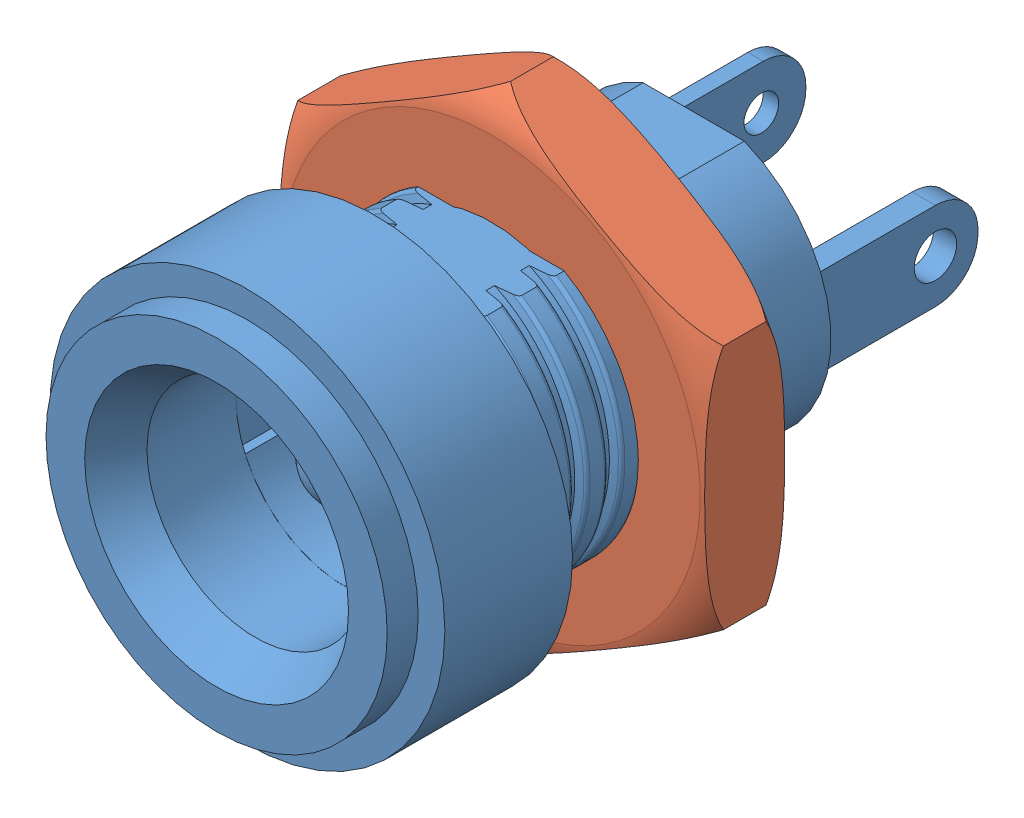
SolidWorks assembly Jack_DC, configuration Predeterminado. Lengths in mm.
Overall size (18.38 17.95 17.63).
2 component instances, 2 part files, 0 mates.
Components (placement in the parent):
- DC Jack Panel Mount Base_1-1: DC Jack Panel Mount Base_1 [Predeterminado] at origin size (10.2 10.2 17.63)
- DC Jack Panel Mount Nut_1-1: DC Jack Panel Mount Nut_1 [Predeterminado] at (0 0 -7.35) x (0.866025 -0.5 0) z (0 0 1) size (13.88 12.71 3.18)
